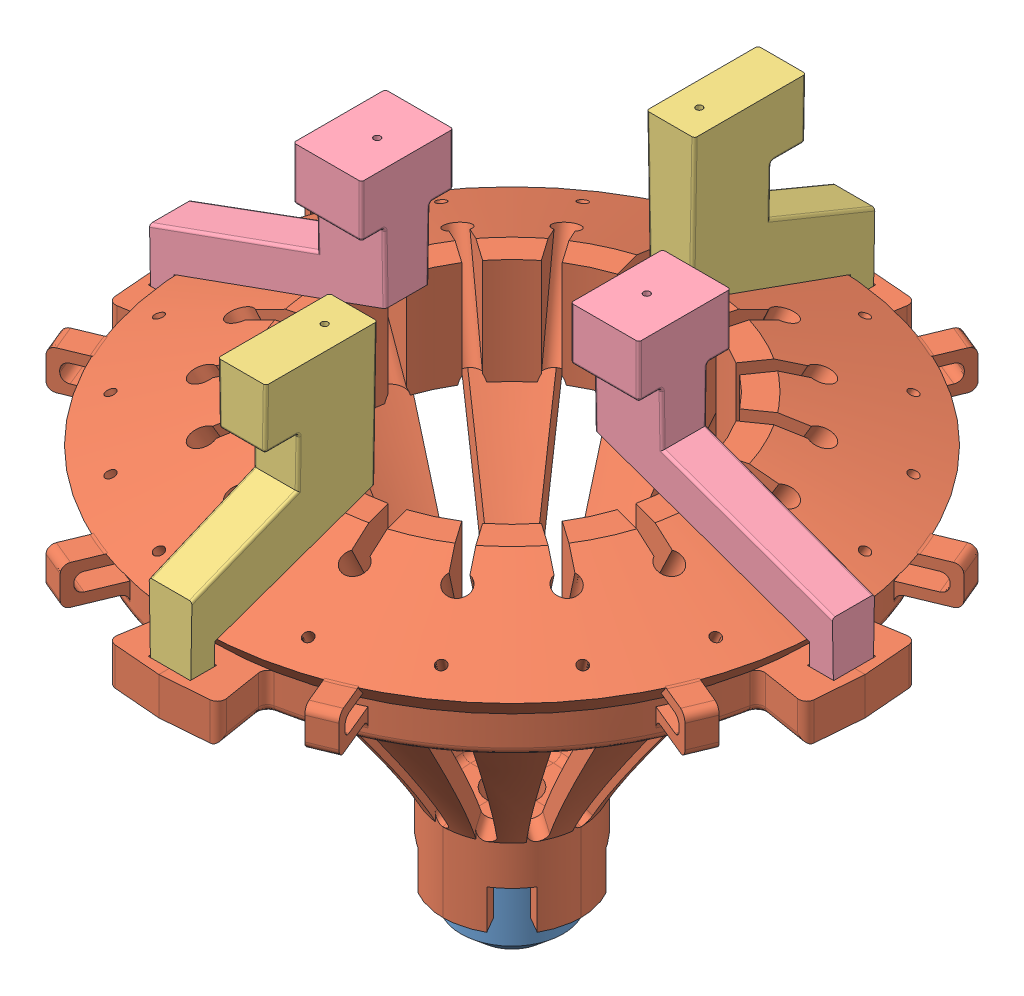
SolidWorks assembly Assy_3D_printed_MARS_v8, configuration Full Drive. Lengths in mm.
Overall size (26.89 23.33 26.89).
9 component instances, 4 part files, 25 mates.
Components (placement in the parent):
- Drive_floor_MARS_V8-1: Drive_floor_MARS_V8 [Default] at origin size (3.89 3.28 3.89)
- Drive_body_MARS_V8-1: Drive_body_MARS_V8 [Default] at (1.9512 5.1356 -1.9438) size (13.49 16.02 13.9)
- Drive_body_MARS_V8-2: Drive_body_MARS_V8 [Default] at (-1.9438 5.1356 -1.9512) x (0 0 -1) z (1 0 0) size (13.49 16.02 13.9)
- Drive_body_MARS_V8-3: Drive_body_MARS_V8 [Default] at (1.9438 5.1356 1.9512) x (0 0 1) z (-1 0 0) size (13.49 16.02 13.9)
- Drive_body_MARS_V8-5: Drive_body_MARS_V8 [Default] at (-1.9512 5.1356 1.9438) x (-1 0 0) z (0 0 -1) size (13.49 16.02 13.9)
- Support_ground_screw_v8-1: Support_ground_screw_v8 [Default] at (0.75 13.3284 -12.9975) x (-1 0 0) z (0 0 -1) size (1.83 9.5 6.97)
- Support_opto_hole_v8-1: Support_opto_hole_v8 [Default] at (6.5354 13.5588 0.75) x (0 0 -1) z (1 0 0) size (3.5 9.5 9.02)
- Support_ground_screw_v8-2: Support_ground_screw_v8 [Default] at (-0.75 13.3284 12.9975) size (1.83 9.5 6.97)
- Support_opto_hole_v8-2: Support_opto_hole_v8 [Default] at (-6.5354 13.5588 -0.75) x (0 0 1) z (-1 0 0) size (3.5 9.5 9.02)
Mates (geometry in assembly coordinates):
- Coincident1: coincident anti-aligned: plane of Drive_floor_MARS_V8-1 through (0 0.9984 0) normal (0 1 0); plane of Drive_body_MARS_V8-1 through (0 0.9984 0) normal (0 -1 0)
- Concentric1: concentric anti-aligned: cylinder of Drive_floor_MARS_V8-1 through (0 0.9984 0) axis (0 1 0) radius 1.3125; cylinder of Drive_body_MARS_V8-1 through (0 3.9984 0) axis (0 -1 0) radius 0.9144
- Concentric2: concentric anti-aligned: cylinder of Drive_floor_MARS_V8-1 through (0 0.9984 0) axis (0 1 0) radius 1.3125; cylinder of Drive_body_MARS_V8-2 through (0 3.9984 0) axis (0 -1 0) radius 0.9144
- Coincident2: coincident anti-aligned: plane of Drive_body_MARS_V8-1 through (0 0.9984 0) normal (-1 0 0); plane of Drive_body_MARS_V8-2 through (0 0.9984 0) normal (1 0 0)
- Coincident4: coincident anti-aligned: plane of Drive_floor_MARS_V8-1 through (0 0.9984 0) normal (0 1 0); plane of Drive_body_MARS_V8-2 through (0 0.9984 0) normal (0 -1 0)
- Coincident5: coordinate: point of Drive_floor_MARS_V8-1; point of assembly
- Coincident6: coincident aligned: plane of Drive_body_MARS_V8-2 through (0 0.9984 0) normal (0 0 1); plane of assembly through (0 0 0) normal (0 0 1)
- Coincident7: coincident anti-aligned: plane of Drive_floor_MARS_V8-1 through (0 0.9984 0) normal (0 1 0); plane of Drive_body_MARS_V8-3 through (0 0.9984 0) normal (0 -1 0)
- Concentric3: concentric anti-aligned: cylinder of Drive_floor_MARS_V8-1 through (0 0.9984 0) axis (0 1 0) radius 1.3125; cylinder of Drive_body_MARS_V8-3 through (0 3.9984 0) axis (0 -1 0) radius 0.9144
- Coincident8: coincident anti-aligned: plane of Drive_body_MARS_V8-1 through (0 0.9984 0) normal (0 0 1); plane of Drive_body_MARS_V8-3 through (0 0.9984 0) normal (0 0 -1)
- Coincident10: coincident anti-aligned: plane of Drive_floor_MARS_V8-1 through (0 0.9984 0) normal (0 1 0); plane of Drive_body_MARS_V8-5 through (0 0.9984 0) normal (0 -1 0)
- Coincident11: coincident anti-aligned: plane of Drive_body_MARS_V8-3 through (0 0.9984 0) normal (-1 0 0); plane of Drive_body_MARS_V8-5 through (0 0.9984 0) normal (1 0 0)
- Concentric5: concentric anti-aligned: cylinder of Drive_floor_MARS_V8-1 through (0 0.9984 0) axis (0 1 0) radius 1.3125; cylinder of Drive_body_MARS_V8-5 through (0 3.9984 0) axis (0 -1 0) radius 0.9144
- Coincident12: coincident anti-aligned: plane of Drive_body_MARS_V8-1 through (0.8 13.3284 -12.0475) normal (0 1 0); plane of Support_ground_screw_v8-1 through (-0.75 13.3284 -12.9975) normal (0 -1 0)
- Width1: width aligned: plane of Support_ground_screw_v8-1 through (-0.75 13.3284 -12.9975) normal (-0.999848 -0.017452 0); plane of Support_ground_screw_v8-1 through (0.75 13.3284 -12.9975) normal (0.999848 -0.017452 0); plane of Drive_body_MARS_V8-2 through (-0.8 5.1356 -1.9512) normal (1 0 0); plane of Drive_body_MARS_V8-1 through (0.8 5.1356 -1.9438) normal (-1 0 0)
- Width2: width aligned: plane of Support_ground_screw_v8-1 through (-0.75 13.3284 -12.9975) normal (0 0 -1); plane of Support_ground_screw_v8-1 through (-0.75 15.2284 -12.0975) normal (0 0 1); plane of Drive_body_MARS_V8-1 through (0.8 14.4284 -12.0475) normal (0 0 -1); plane of Drive_body_MARS_V8-1 through (0.8 13.3284 -13.0475) normal (0 0 1)
- Coincident13: coincident anti-aligned: plane of Drive_body_MARS_V8-3 through (12.0475 13.3284 0.8) normal (0 1 0); plane of Support_opto_hole_v8-1 through (12.9975 13.3284 -0.75) normal (0 -1 0)
- Width4: width aligned: plane of Support_opto_hole_v8-1 through (6.5354 13.5588 -0.75) normal (0 -0.017452 -0.999848); plane of Support_opto_hole_v8-1 through (6.5354 13.5588 0.75) normal (0 -0.017452 0.999848); plane of Drive_body_MARS_V8-1 through (1.9512 5.1356 -0.8) normal (0 0 1); plane of Drive_body_MARS_V8-3 through (1.9438 5.1356 0.8) normal (0 0 -1)
- Width5: width anti-aligned: plane of Support_opto_hole_v8-1 through (12.9975 13.3284 -0.75) normal (1 0 0); plane of Support_opto_hole_v8-1 through (12.0975 15.2284 -0.75) normal (-1 0 0); plane of Drive_body_MARS_V8-1 through (13.0475 13.3284 -0.8) normal (-1 0 0); plane of Drive_body_MARS_V8-1 through (12.0475 14.4284 -0.8) normal (1 0 0)
- Coincident14: coincident anti-aligned: plane of Drive_body_MARS_V8-5 through (-0.8 13.3284 12.0475) normal (0 1 0); plane of Support_ground_screw_v8-2 through (0.75 13.3284 12.9975) normal (0 -1 0)
- Width6: width aligned: plane of Support_ground_screw_v8-2 through (0.75 13.3284 12.9975) normal (0.999848 -0.017452 0); plane of Support_ground_screw_v8-2 through (-0.75 13.3284 12.9975) normal (-0.999848 -0.017452 0); plane of Drive_body_MARS_V8-3 through (0.8 5.1356 1.9512) normal (-1 0 0); plane of Drive_body_MARS_V8-5 through (-0.8 5.1356 1.9438) normal (1 0 0)
- Width7: width anti-aligned: plane of Support_ground_screw_v8-2 through (0.75 13.3284 12.9975) normal (0 0 1); plane of Support_ground_screw_v8-2 through (0.75 15.2284 12.0975) normal (0 0 -1); plane of Drive_body_MARS_V8-5 through (-0.8 13.3284 13.0475) normal (0 0 -1); plane of Drive_body_MARS_V8-5 through (-0.8 14.4284 12.0475) normal (0 0 1)
- Coincident15: coincident anti-aligned: plane of Drive_body_MARS_V8-2 through (-12.0475 13.3284 -0.8) normal (0 1 0); plane of Support_opto_hole_v8-2 through (-12.9975 13.3284 0.75) normal (0 -1 0)
- Width8: width aligned: plane of Support_opto_hole_v8-2 through (-6.5354 13.5588 0.75) normal (0 -0.017452 0.999848); plane of Support_opto_hole_v8-2 through (-6.5354 13.5588 -0.75) normal (0 -0.017452 -0.999848); plane of Drive_body_MARS_V8-5 through (-1.9512 5.1356 0.8) normal (0 0 -1); plane of Drive_body_MARS_V8-2 through (-1.9438 5.1356 -0.8) normal (0 0 1)
- Width9: width aligned: plane of Support_opto_hole_v8-2 through (-12.9975 13.3284 0.75) normal (-1 0 0); plane of Support_opto_hole_v8-2 through (-12.0975 15.2284 0.75) normal (1 0 0); plane of Drive_body_MARS_V8-2 through (-12.0475 14.4284 -0.8) normal (-1 0 0); plane of Drive_body_MARS_V8-2 through (-13.0475 13.3284 -0.8) normal (1 0 0)
